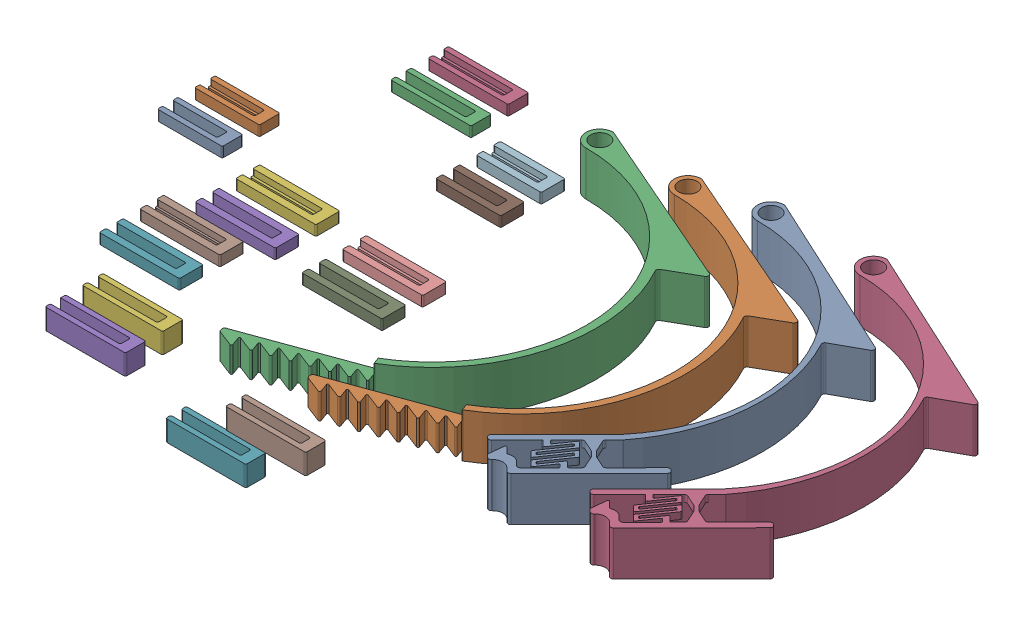
SolidWorks assembly ArmBandforPrinting v4, configuration Default. Lengths in mm.
Overall size (168.07 54.41 135.21).
13 component instances, 10 part files, 3 mates.
Components (placement in the parent):
- Arm Clamp v3.1-1: Arm Clamp v3.1 [Default] at (-24.1915 6.5795 8.2955) size (55.12 13 108.47)
- Arm Clamp inner v3.2-1: Arm Clamp inner v3.2 [Default] at (-43.0146 6.5795 13.8257) size (60.61 13 107.28)
- Arm Clamp inner v3.2-2: Arm Clamp inner v3.2 [Default] at (-67.7485 6.5795 14.9374) size (60.61 13 107.28)
- Arm Clamp v3.1-2: Arm Clamp v3.1 [Default] at (4.6423 6.5795 7.0902) size (55.12 13 108.47)
- HRclip v8-1: HRclip v8 [Default] at (-91.093 36.8462 49.2699) x (1 0 0) z (0 1 0) size (23.5 18.9 3)
- HRclip v7-1: HRclip v7 [Default] at (-106.918 27.3613 61.5515) x (1 0 0) z (0 1 0) size (23.5 18.9 3)
- HRclip v6-1: HRclip v6 [Default] at (-63.7644 30.5779 45.3307) x (1 0 0) z (0 1 0) size (23.5 18.9 3)
- HRclip v5-1: HRclip v5 [Default] at (-96.6166 2.0053 -26.7704) x (1 0 0) z (0 1 0) size (19 18.9 3)
- HRclip v4-1: HRclip v4 [Default] at (-112.3153 44.7136 40.0873) x (1 0 0) z (0 1 0) size (19 16.9 3)
- HRclip v3-1: HRclip v3 [Default] at (-111.3 18.9869 -27.2636) x (1 0 0) z (0 1 0) size (23.5 16.9 3)
- HRclip v2-1: HRclip v2 [Default] at (-106.8949 13.4208 78.4056) x (1 0 0) z (0 1 0) size (23.5 16.9 6)
- HRclip v1-1: HRclip v1 [Default] at (-81.0693 -0.6976 73.8262) x (1 0 0) z (0 -1 0) size (23.5 6 6)
- HRclip v1-2: HRclip v1 [Default] at (-68.5443 6.0824 68.7965) x (1 0 0) z (0 -1 0) size (23.5 6 6)
Mates (geometry in assembly coordinates):
- Coincident1: coincident aligned: plane of Arm Clamp v3.1-1 through (-24.1915 6.5795 8.2955) normal (0 -1 0); plane of Arm Clamp v3.1-2 through (4.6423 6.5795 7.0902) normal (0 -1 0)
- Coincident2: coincident aligned: plane of Arm Clamp v3.1-1 through (-24.1915 6.5795 8.2955) normal (0 -1 0); plane of Arm Clamp inner v3.2-1 through (-43.0146 6.5795 13.8257) normal (0 -1 0)
- Coincident3: coincident aligned: plane of Arm Clamp v3.1-1 through (-24.1915 6.5795 8.2955) normal (0 -1 0); plane of Arm Clamp inner v3.2-2 through (-67.7485 6.5795 14.9374) normal (0 -1 0)
